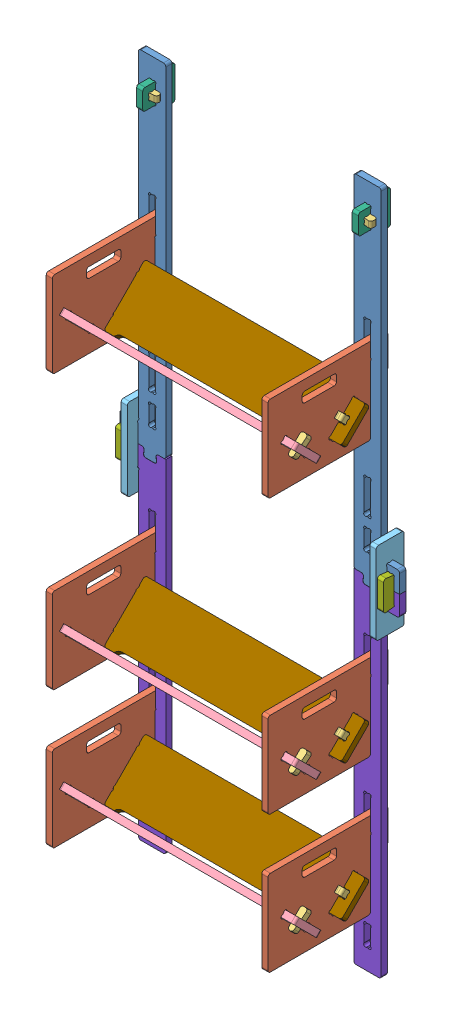
SolidWorks assembly growall, configuration Défaut. Lengths in mm.
Overall size (817 2000 358).
36 component instances, 9 part files, 29 mates.
Components (placement in the parent):
- post-2: post [Default] at (0 0 18) x (-1 0 0) z (0 0 -1) size (134 1025 18)
- shelf_side-1: shelf_side [Défaut] at (-31.5 -601 -32) x (0 0 1) z (-1 0 0) size (350 250 18)
- pin-1: pin [Défaut] at (-57.3913 -761.8891 256.0312) x (-1 0 0) z (0 -0.707107 -0.707107) size (19.55 57.89 18)
- beam-1: beam [Défaut] at (634.5 -728.3015 279.7193) x (0 -0.707107 -0.707107) z (0 0.707107 -0.707107) size (187.99 720 18)
- connector2-1: connector2 [Default] at (-80 -120.5 -31.5) x (0 0 1) z (-1 0 0) size (82 240 18)
- connector3-1: connector3 [Défaut] at (-31.5 880.5 54) x (0 1 0) z (-1 0 0) size (100 94 18)
- connector4-1: connector4 [Default] at (-99 -39.5 -12) x (0 0 1) z (-1 0 0) size (60 86.01 18)
- post2-1: post2 [Default] x (-1 0 0) z (0 0 1) size (134 1000 18)
- beam2-2: beam2 [Défaut] at (634.5 -799.0122 126.9914) x (0 0.707107 -0.707107) z (0 0.707107 0.707107) size (169.49 720 18)
- pin-14: pin [Défaut] at (-57.3913 -774.617 92.6967) x (-1 0 0) z (0 0.707107 -0.707107) size (19.55 57.89 18)
- pin-15: pin [Défaut] at (606.3913 -761.8891 79.9688) x (1 0 0) z (0 -0.707107 0.707107) size (19.55 57.89 18)
- pin-16: pin [Défaut] at (606.3913 -774.617 243.3033) x (1 0 0) z (0 0.707107 0.707107) size (19.55 57.89 18)
- shelf_side-10: shelf_side [Défaut] at (598.5 -601 -32) x (0 0 1) z (-1 0 0) size (350 250 18)
- post2-2: post2 [Default] at (549 0 18) x (1 0 0) z (0 0 -1) size (134 1000 18)
- post-8: post [Default] at (549 0 0) size (134 1025 18)
- connector2-2: connector2 [Default] at (647 -120.5 -31.5) x (0 0 1) z (-1 0 0) size (82 240 18)
- connector4-2: connector4 [Default] at (666 -39.5 -12) x (0 0 1) z (-1 0 0) size (60 86.01 18)
- pin-17: pin [Défaut] at (-19.5 920 25.8913) x (0 0 1) z (0 -1 0) size (19.55 57.89 18)
- connector3-2: connector3 [Défaut] at (598.5 880.5 54) x (0 1 0) z (-1 0 0) size (100 94 18)
- pin-18: pin [Défaut] at (568.5 902 25.8913) x (0 0 1) z (0 1 0) size (19.55 57.89 18)
- shelf_side-11: shelf_side [Défaut] at (598.5 -201 -32) x (0 0 1) z (-1 0 0) size (350 250 18)
- shelf_side-13: shelf_side [Défaut] at (598.5 599 -32) x (0 0 1) z (-1 0 0) size (350 250 18)
- shelf_side-14: shelf_side [Défaut] at (-31.5 -201 -32) x (0 0 1) z (-1 0 0) size (350 250 18)
- shelf_side-16: shelf_side [Défaut] at (-31.5 599 -32) x (0 0 1) z (-1 0 0) size (350 250 18)
- pin-19: pin [Défaut] at (-57.3913 -361.8891 256.0312) x (-1 0 0) z (0 -0.707107 -0.707107) size (19.55 57.89 18)
- pin-21: pin [Défaut] at (-57.3913 438.1109 256.0312) x (-1 0 0) z (0 -0.707107 -0.707107) size (19.55 57.89 18)
- pin-22: pin [Défaut] at (-57.3913 -374.617 92.6967) x (-1 0 0) z (0 0.707107 -0.707107) size (19.55 57.89 18)
- pin-24: pin [Défaut] at (-57.3913 425.383 92.6967) x (-1 0 0) z (0 0.707107 -0.707107) size (19.55 57.89 18)
- beam-2: beam [Défaut] at (634.5 -328.3015 279.7193) x (0 -0.707107 -0.707107) z (0 0.707107 -0.707107) size (187.99 720 18)
- beam-4: beam [Défaut] at (634.5 471.6985 279.7193) x (0 -0.707107 -0.707107) z (0 0.707107 -0.707107) size (187.99 720 18)
- beam2-3: beam2 [Défaut] at (634.5 -399.0122 126.9914) x (0 0.707107 -0.707107) z (0 0.707107 0.707107) size (169.49 720 18)
- beam2-5: beam2 [Défaut] at (634.5 400.9878 126.9914) x (0 0.707107 -0.707107) z (0 0.707107 0.707107) size (169.49 720 18)
- pin-25: pin [Défaut] at (606.3913 -374.617 243.3033) x (1 0 0) z (0 0.707107 0.707107) size (19.55 57.89 18)
- pin-27: pin [Défaut] at (606.3913 425.383 243.3033) x (1 0 0) z (0 0.707107 0.707107) size (19.55 57.89 18)
- pin-28: pin [Défaut] at (606.3913 -361.8891 79.9688) x (1 0 0) z (0 -0.707107 0.707107) size (19.55 57.89 18)
- pin-30: pin [Défaut] at (606.3913 438.1109 79.9688) x (1 0 0) z (0 -0.707107 0.707107) size (19.55 57.89 18)
Mates (geometry in assembly coordinates):
- Coïncidente35: coincident: point of post2-1; point of assembly
- Coïncidente45: coincident anti-aligned: plane of shelf_side-1 through (-31.5 -601 -32) normal (1 0 0); plane of beam-1 through (-31.5 -709.9254 272.6396) normal (-1 0 0)
- Coïncidente49: coincident anti-aligned: plane of shelf_side-1 through (-49.5 -601 -32) normal (-1 0 0); plane of pin-1 through (-49.5 -739.2617 207.948) normal (1 0 0)
- Coïncidente51: coincident anti-aligned: plane of pin-1 through (-57.3913 -761.8891 256.0312) normal (0 0.707107 0.707107); plane of beam-1 through (-57.2512 -744.2114 238.3536) normal (0 -0.707107 -0.707107)
- Coïncidente59: coincident anti-aligned: plane of shelf_side-1 through (-31.5 -601 -32) normal (1 0 0); plane of beam2-2 through (-31.5 -792.4683 145.9034) normal (-1 0 0)
- Distance5: distance = 20 mm aligned: plane of connector3-1 through (-49.5 883 7.9878) normal (-1 0 0); plane of pin-17 through (-69.5 902 18) normal (-1 0 0)
- Coïncidente81: coincident: plane of pin-1 through (-69.6872 -739.2617 207.948) normal (-0.996195 -0.061628 0.061628); line of beam-1 through (-67.5 -749.6924 232.8726) axis (0 -0.707107 -0.707107)
- Coincident2: coincident: point of post2-1; point of assembly
- Coincident3: coincident anti-aligned: plane of shelf_side-1 through (-49.5 -601 -32) normal (-1 0 0); plane of post2-1 through (-49.5 -642.7488 18) normal (1 0 0)
- Coincident4: coincident anti-aligned: plane of shelf_side-1 through (-49.5 -650.5 9.7488) normal (0 -1 0); plane of post2-1 through (-38.2512 -650.5 18) normal (0 1 0)
- Coincident5: coincident anti-aligned: plane of shelf_side-1 through (-49.5 -851 18) normal (0 0 -1); plane of post2-1 through (-75 -68.7456 18) normal (0 0 1)
- Coincident6: coincident anti-aligned: plane of shelf_side-1 through (-49.5 -721.0545 74.4896) normal (0 -0.707107 -0.707107); plane of beam2-2 through (589.2456 -782.7487 136.1838) normal (0 0.707107 0.707107)
- Coincident7: coincident anti-aligned: plane of shelf_side-1 through (-49.5 -721.0545 63.5277) normal (0 -0.707107 0.707107); plane of beam2-2 through (-85.5 -715.5736 69.0086) normal (0 0.707107 -0.707107)
- Coincident9: coincident anti-aligned: plane of shelf_side-1 through (-49.5 -721.0545 272.4723) normal (0 -0.707107 -0.707107); plane of beam-1 through (-85.5 -715.5736 266.9914) normal (0 0.707107 0.707107)
- Coincident10: coincident anti-aligned: plane of shelf_side-1 through (-49.5 -721.0545 261.5104) normal (0 -0.707107 0.707107); plane of beam-1 through (588.4878 -717.3414 265.2236) normal (0 0.707107 -0.707107)
- Coincident11: coincident aligned: plane of post-2 through (-87.9878 57.5 18) normal (0 0 1); plane of post2-1 through (-75 -68.7456 18) normal (0 0 1)
- Coincident12: coincident aligned: plane of post-2 through (-134 60 0) normal (-1 0 0); plane of post2-1 through (-134 -60 18) normal (-1 0 0)
- Coincident13: coincident anti-aligned: plane of post-2 through (-62 0 0) normal (0 -1 0); plane of post2-1 through (-62.5064 0 18) normal (0 1 0)
- Coincident14: coincident anti-aligned: plane of post-2 through (-117 32.7488 0) normal (1 0 0); plane of connector4-1 through (-117 -39.5 -12) normal (-1 0 0)
- Coincident15: coincident anti-aligned: plane of post-2 through (-105.7512 40.5 0) normal (0 -1 0); plane of connector4-1 through (-117 40.5 -12) normal (0 1 0)
- Coincident16: coincident: line of post-2 through (-109.2488 40.5 18) axis (1 0 0); plane of connector4-1 through (-117 40.5 18) normal (0 0.991228 -0.132164)
- Coincident17: coincident anti-aligned: plane of post-2 through (-87.9878 57.5 0) normal (0 0 -1); plane of connector2-1 through (-98 -53.2488 0) normal (0 0 1)
- Coincident18: coincident anti-aligned: plane of post-2 through (-80 67.9878 0) normal (-1 0 0); plane of connector2-1 through (-80 -120.5 -31.5) normal (1 0 0)
- Coincident19: coincident anti-aligned: plane of post-2 through (-87.9878 60 0) normal (0 1 0); plane of connector2-1 through (-98 60 7.7512) normal (0 -1 0)
- Coincident20: coincident anti-aligned: plane of post-2 through (-49.5 887.2512 0) normal (1 0 0); plane of connector3-1 through (-49.5 883 7.9878) normal (-1 0 0)
- Coincident21: coincident anti-aligned: plane of post-2 through (-87.9878 57.5 0) normal (0 0 -1); plane of connector3-1 through (-49.5 948.4878 0) normal (0 0 1)
- Coincident22: coincident anti-aligned: plane of post-2 through (-38.2512 940.5 0) normal (0 -1 0); plane of connector3-1 through (-49.5 940.5 54) normal (0 1 0)
- Coincident23: coincident anti-aligned: plane of connector3-1 through (-49.5 920 25.7512) normal (0 -1 0); plane of pin-17 through (-19.5 920 25.8913) normal (0 1 0)
- Coincident24: coincident anti-aligned: plane of connector3-1 through (-49.5 908.7512 18) normal (0 0 1); plane of pin-17 through (-69.5 902 18) normal (0 0 -1)
